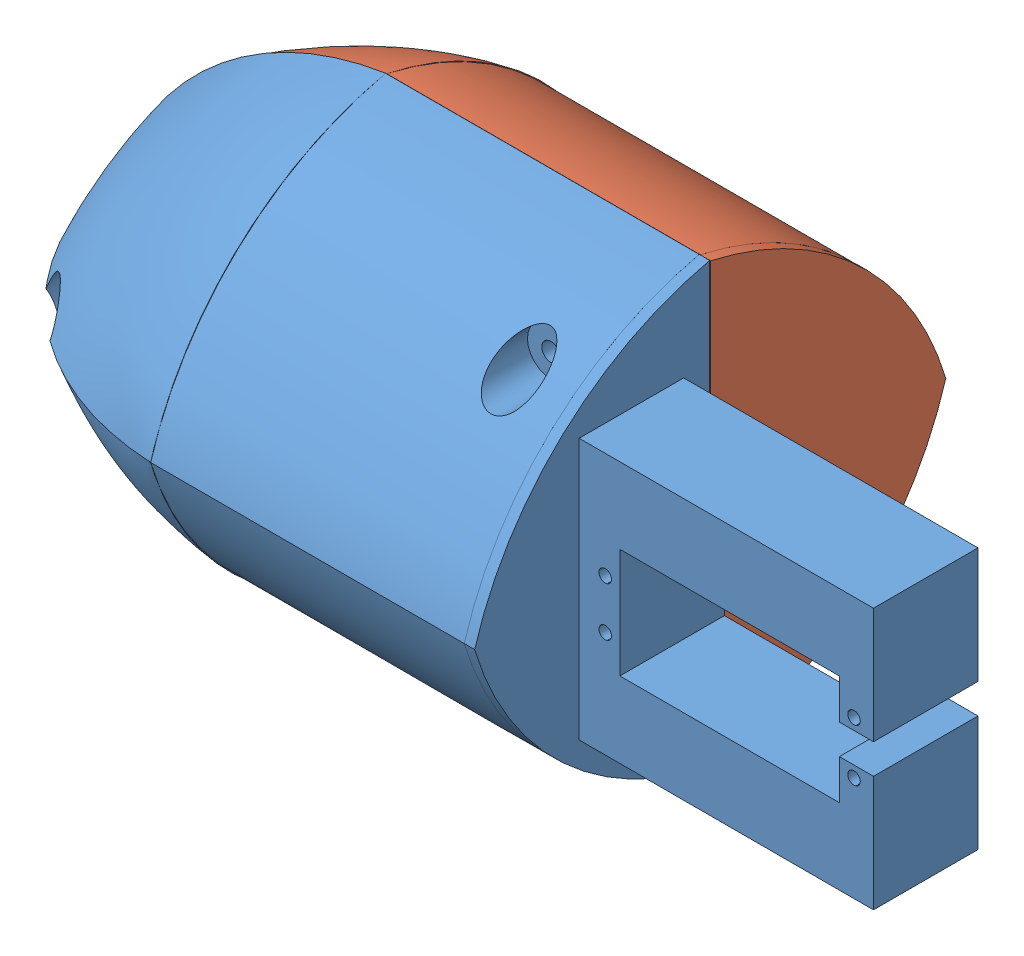
SolidWorks assembly 組合件1, configuration 預設. Lengths in mm.
Overall size (169.89 88.88 91.13).
2 component instances, 2 part files, 3 mates.
Components (placement in the parent):
- down-1: down [預設] at (-105.8885 -2.5953 148.3496) size (169.89 88 47.86)
- top-1: top [預設] at (-105.7263 -2.5953 148.3496) x (1 0 0) z (0 0 -1) size (113.56 88 48.05)
Mates (geometry in assembly coordinates):
- 重合/共線/共點1: coincident: line of down-1 through (-54.4285 39.4047 148.3496) axis (1 0 0); cylinder of top-1 through (-54.2663 -19.8297 161.528) axis (1 0 0) radius 60.6827
- 重合/共線/共點2: coincident: plane of down-1 through (-44.3017 20.3379 148.3496) normal (0 0 -1); plane of top-1 through (-44.1395 -25.5284 148.3496) normal (0 0 1)
- 重合/共線/共點3: coincident: line of down-1 through (-54.4285 -44.5953 148.3496) axis (1 0 0); line of top-1 through (-54.2663 -44.5953 148.3496) axis (1 0 0)
